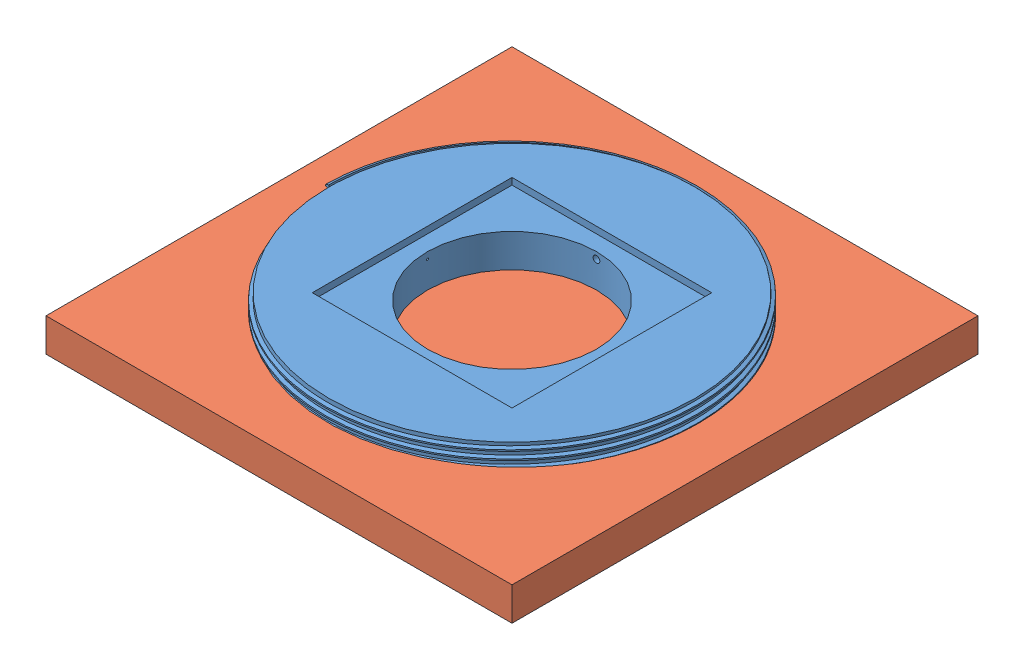
SolidWorks assembly Assembled pieces, configuration Default. Lengths in mm.
Overall size (70 8.42 70).
2 component instances, 2 part files, 8 mates.
Components (placement in the parent):
- innerCircle-1: innerCircle [Default] at origin size (56.72 6.89 56.61)
- Bottom-1: Bottom [Default] x (1 0 0) z (0 1 0) size (70 70 8)
Mates (geometry in assembly coordinates):
- InPlace1: in place: plane of innerCircle-1 through (0 0 0) normal (0 -1 0); plane of ? through (0 0 0) normal (0 -1 0); moOrthogonalPlaneRef_w of innerCircle-1 through (0 0 0) normal (0 -1 0); unknown of ?; plane of innerCircle-1 through (0 0 0) normal (0 -1 0); line of ? through (55 -55 0) axis (0 0 -1); plane of innerCircle-1 through (0 0 0) normal (0 -1 0); unknown of ?
- Coincident1: coincident aligned: plane of innerCircle-1; plane of ?
- Coincident2: coincident aligned: moOrthogonalPlaneRef_w of innerCircle-1 through (0 0 0) normal (0 0 -1); plane of ?
- Coincident3: coincident anti-aligned: moOrthogonalPlaneRef_w of innerCircle-1 through (0 0 0) normal (1 0 0); plane of ?
- InPlace2: in place: plane of Bottom-1 through (0 0 0) normal (0 1 0); plane of Bottom-1 through (0 0 0) normal (0 0 -1); line of Bottom-1 through (55 -55 0) axis (0 0 1); unknown of Bottom-1
- Coincident1: coincident aligned: plane of Bottom-1; plane of assembly
- Coincident2: coincident aligned: plane of Bottom-1 through (0 0 0) normal (0 0 -1); moOrthogonalPlaneRef_w of assembly
- Coincident3: coincident anti-aligned: plane of Bottom-1; moOrthogonalPlaneRef_w of assembly
